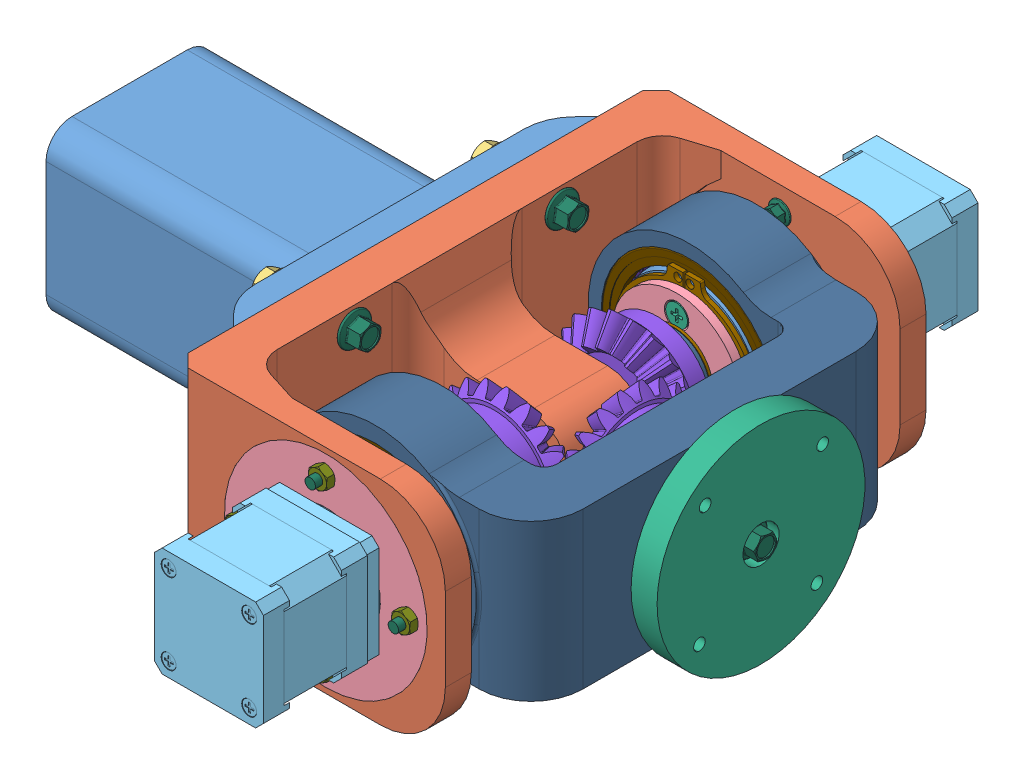
SolidWorks assembly Wrist assembly v2, configuration Default. Lengths in mm.
Overall size (245 113 275).
266 component instances, 29 part files, 123 mates.
Components (placement in the parent):
- Wrist mount-1: Wrist mount [Default] at (124.8037 132.1367 221.4307) x (-1 0 0) z (0 0 -1) size (110 82 140)
- Wrist input frame-2: Wrist input frame [Default] at (124.8037 91.1367 221.4307) x (0 0 -1) z (0 -1 0) size (185 104 82)
- hex flange nut_am-1: hex flange nut_am [M6 hex nut] at (108.8037 165.6367 263.4307) x (0 0 1) z (-1 0 0) size (14.2 14.2 6)
- hex flange nut_am-2: hex flange nut_am [M6 hex nut] at (108.8037 98.6367 263.4307) x (0 0 1) z (-1 0 0) size (14.2 14.2 6)
- Motor sleeve-2: Motor sleeve [Default] at (182.8037 132.1367 313.9307) x (0 0 -1) z (0 -1 0) size (50 78 78)
- 17HS15-1684D-HG10-AR3-1: 17HS15-1684D-HG10-AR3 [Default] at (182.8037 132.1367 123.9307) x (0 -1 0) z (0 0 1) size (42.88 42 103.5)
- 17HS15-1684D-HG10-AR3-2: 17HS15-1684D-HG10-AR3 [Default] at (182.8037 132.1367 318.9307) x (0 -1 0) z (0 0 -1) size (42.88 42 103.5)
- flat head screw_am-7: flat head screw_am [M4 16mm flat head screw] at (165.3037 132.1367 263.9307) x (0 0 1) z (-1 0 0) size (16 8.4 8.4)
- flat head screw_am-8: flat head screw_am [M4 16mm flat head screw] at (182.8037 149.6367 263.9307) x (0 0 1) z (-1 0 0) size (16 8.4 8.4)
- flat head screw_am-9: flat head screw_am [M4 16mm flat head screw] at (200.3037 132.1367 263.9307) x (0 0 1) z (-1 0 0) size (16 8.4 8.4)
- flat head screw_am-11: flat head screw_am [M4 16mm flat head screw] at (182.8037 114.6367 263.9307) x (0 0 1) z (-1 0 0) size (16 8.4 8.4)
- shaft-1: shaft [Default] at (182.8037 132.1367 166.9307) x (0 0 1) z (-0.856245 0.51657 0) size (53 17 17)
- straight miter gear_am-1: straight miter gear_am [A 1C 4MYKW25020] at (182.8037 132.1367 193.8048) x (0 0 1) z (0.856245 -0.51657 0) size (19.66 53.34 53.34)
- shaft-2: shaft [Default] at (182.8037 132.1367 275.9307) x (0 0 -1) z (0.128933 -0.991653 0) size (53 17 17)
- straight miter gear_am-2: straight miter gear_am [A 1C 4MYKW25020] at (182.8037 132.1367 249.0566) x (0 0 -1) z (-0.128933 0.991653 0) size (19.66 53.34 53.34)
- basic external retaining ring_am-1: basic external retaining ring_am [50mm retaining ring] at (182.8037 132.1367 174.1307) x (0.99991 0.013423 0) z (0 0 -1) size (54.93 58.5 1.6)
- basic external retaining ring_am-2: basic external retaining ring_am [50mm retaining ring] at (182.8037 132.1367 267.1307) x (0.99991 0.013423 0) z (0 0 -1) size (54.93 58.5 1.6)
- Wrist output frame-1: Wrist output frame [Default] at (182.8037 132.1367 293.9307) x (0 0 -1) z (0 -1 0) size (151.4 102 78)
- Output shaft-1: Output shaft [Default] at (198.8037 132.1367 221.4307) x (0 -0.779859 0.625955) z (1 0 0) size (18 18 51)
- straight miter gear_am-3: straight miter gear_am [A 1C 4MYKW25020] at (210.4297 132.1367 221.4307) x (-1 0 0) z (0 -0.779859 0.625955) size (19.66 53.34 53.34)
- Motor sleeve-3: Motor sleeve [Default] at (182.8037 132.1367 128.9307) x (0 0 1) z (1 0 0) size (50 78 78)
- hex flange nut_am-5: hex flange nut_am [M6 hex nut] at (108.8037 165.6367 179.4307) x (0 0 1) z (-1 0 0) size (14.2 14.2 6)
- hex flange nut_am-6: hex flange nut_am [M6 hex nut] at (108.8037 98.6367 179.4307) x (0 0 1) z (-1 0 0) size (14.2 14.2 6)
- flat head screw_am-12: flat head screw_am [M4 16mm flat head screw] at (182.8037 149.6367 178.9307) x (0 0 -1) z (1 0 0) size (16 8.4 8.4)
- flat head screw_am-13: flat head screw_am [M4 16mm flat head screw] at (200.3037 132.1367 178.9307) x (0 0 -1) z (1 0 0) size (16 8.4 8.4)
- flat head screw_am-14: flat head screw_am [M4 16mm flat head screw] at (165.3037 132.1367 178.9307) x (0 0 -1) z (1 0 0) size (16 8.4 8.4)
- flat head screw_am-15: flat head screw_am [M4 16mm flat head screw] at (182.8037 114.6367 178.9307) x (0 0 -1) z (1 0 0) size (16 8.4 8.4)
- HK_1412-4: HK_1412 [Default] at (182.8037 132.1367 236.4307) x (0 0 -1) z (0.167203 -0.985923 0) size (12 20 20)
  - HK_1412_3-1: HK_1412_3 [Default] x (1 0 0) z (0 -0.382683 0.92388) size (7.3 2 2)
  - HK_1412_3-2: HK_1412_3 [Default] x (1 0 0) z (0 -0.707107 0.707107) size (7.3 2 2)
  - HK_1412_3-3: HK_1412_3 [Default] x (1 0 0) z (0 -0.92388 0.382683) size (7.3 2 2)
  - HK_1412_3-4: HK_1412_3 [Default] x (1 0 0) z (0 -1 0) size (7.3 2 2)
  - HK_1412_3-5: HK_1412_3 [Default] x (1 0 0) z (0 -0.92388 -0.382683) size (7.3 2 2)
  - HK_1412_3-6: HK_1412_3 [Default] x (1 0 0) z (0 -0.707107 -0.707107) size (7.3 2 2)
  - HK_1412_3-7: HK_1412_3 [Default] x (1 0 0) z (0 -0.382683 -0.92388) size (7.3 2 2)
  - HK_1412_3-8: HK_1412_3 [Default] x (1 0 0) z (0 0 -1) size (7.3 2 2)
  - HK_1412_3-9: HK_1412_3 [Default] x (1 0 0) z (0 0.382683 -0.92388) size (7.3 2 2)
  - HK_1412_3-10: HK_1412_3 [Default] x (1 0 0) z (0 0.707107 -0.707107) size (7.3 2 2)
  - HK_1412_3-11: HK_1412_3 [Default] x (1 0 0) z (0 0.92388 -0.382683) size (7.3 2 2)
  - HK_1412_3-12: HK_1412_3 [Default] x (1 0 0) z (0 1 0) size (7.3 2 2)
  - HK_1412_3-13: HK_1412_3 [Default] x (1 0 0) z (0 0.92388 0.382683) size (7.3 2 2)
  - HK_1412_3-14: HK_1412_3 [Default] x (1 0 0) z (0 0.707107 0.707107) size (7.3 2 2)
  - HK_1412_3-15: HK_1412_3 [Default] x (1 0 0) z (0 0.382683 0.92388) size (7.3 2 2)
  - HK_1412_3-16: HK_1412_3 [Default] at origin size (7.3 2 2)
  - HK_1412_20-1: HK_1412_20 [Default] x (1 0 0) z (0 -0.382683 0.92388) size (7.3 2 2)
  - HK_1412_20-2: HK_1412_20 [Default] x (1 0 0) z (0 -0.707107 0.707107) size (7.3 2 2)
  - HK_1412_20-3: HK_1412_20 [Default] x (1 0 0) z (0 -0.92388 0.382683) size (7.3 2 2)
  - HK_1412_20-4: HK_1412_20 [Default] x (1 0 0) z (0 -1 0) size (7.3 2 2)
  - HK_1412_20-5: HK_1412_20 [Default] x (1 0 0) z (0 -0.92388 -0.382683) size (7.3 2 2)
  - HK_1412_20-6: HK_1412_20 [Default] x (1 0 0) z (0 -0.707107 -0.707107) size (7.3 2 2)
  - HK_1412_20-7: HK_1412_20 [Default] x (1 0 0) z (0 -0.382683 -0.92388) size (7.3 2 2)
  - HK_1412_20-8: HK_1412_20 [Default] x (1 0 0) z (0 0 -1) size (7.3 2 2)
  - HK_1412_20-9: HK_1412_20 [Default] x (1 0 0) z (0 0.382683 -0.92388) size (7.3 2 2)
  - HK_1412_20-10: HK_1412_20 [Default] x (1 0 0) z (0 0.707107 -0.707107) size (7.3 2 2)
  - HK_1412_20-11: HK_1412_20 [Default] x (1 0 0) z (0 0.92388 -0.382683) size (7.3 2 2)
  - HK_1412_20-12: HK_1412_20 [Default] x (1 0 0) z (0 1 0) size (7.3 2 2)
  - HK_1412_20-13: HK_1412_20 [Default] x (1 0 0) z (0 0.92388 0.382683) size (7.3 2 2)
  - HK_1412_20-14: HK_1412_20 [Default] x (1 0 0) z (0 0.707107 0.707107) size (7.3 2 2)
  - HK_1412_20-15: HK_1412_20 [Default] x (1 0 0) z (0 0.382683 0.92388) size (7.3 2 2)
  - HK_1412_20-16: HK_1412_20 [Default] at origin size (7.3 2 2)
  - HK_1412_37-1: HK_1412_37 [Default] at origin size (12 20 20)
- HK_1412-5: HK_1412 [Default] at (182.8037 132.1367 206.4307) x (0 0 1) z (0.606827 -0.794834 0) size (12 20 20)
  - HK_1412_3-1: HK_1412_3 [Default] x (1 0 0) z (0 -0.382683 0.92388) size (7.3 2 2)
  - HK_1412_3-2: HK_1412_3 [Default] x (1 0 0) z (0 -0.707107 0.707107) size (7.3 2 2)
  - HK_1412_3-3: HK_1412_3 [Default] x (1 0 0) z (0 -0.92388 0.382683) size (7.3 2 2)
  - HK_1412_3-4: HK_1412_3 [Default] x (1 0 0) z (0 -1 0) size (7.3 2 2)
  - HK_1412_3-5: HK_1412_3 [Default] x (1 0 0) z (0 -0.92388 -0.382683) size (7.3 2 2)
  - HK_1412_3-6: HK_1412_3 [Default] x (1 0 0) z (0 -0.707107 -0.707107) size (7.3 2 2)
  - HK_1412_3-7: HK_1412_3 [Default] x (1 0 0) z (0 -0.382683 -0.92388) size (7.3 2 2)
  - HK_1412_3-8: HK_1412_3 [Default] x (1 0 0) z (0 0 -1) size (7.3 2 2)
  - HK_1412_3-9: HK_1412_3 [Default] x (1 0 0) z (0 0.382683 -0.92388) size (7.3 2 2)
  - HK_1412_3-10: HK_1412_3 [Default] x (1 0 0) z (0 0.707107 -0.707107) size (7.3 2 2)
  - HK_1412_3-11: HK_1412_3 [Default] x (1 0 0) z (0 0.92388 -0.382683) size (7.3 2 2)
  - HK_1412_3-12: HK_1412_3 [Default] x (1 0 0) z (0 1 0) size (7.3 2 2)
  - HK_1412_3-13: HK_1412_3 [Default] x (1 0 0) z (0 0.92388 0.382683) size (7.3 2 2)
  - HK_1412_3-14: HK_1412_3 [Default] x (1 0 0) z (0 0.707107 0.707107) size (7.3 2 2)
  - HK_1412_3-15: HK_1412_3 [Default] x (1 0 0) z (0 0.382683 0.92388) size (7.3 2 2)
  - HK_1412_3-16: HK_1412_3 [Default] at origin size (7.3 2 2)
  - HK_1412_20-1: HK_1412_20 [Default] x (1 0 0) z (0 -0.382683 0.92388) size (7.3 2 2)
  - HK_1412_20-2: HK_1412_20 [Default] x (1 0 0) z (0 -0.707107 0.707107) size (7.3 2 2)
  - HK_1412_20-3: HK_1412_20 [Default] x (1 0 0) z (0 -0.92388 0.382683) size (7.3 2 2)
  - HK_1412_20-4: HK_1412_20 [Default] x (1 0 0) z (0 -1 0) size (7.3 2 2)
  - HK_1412_20-5: HK_1412_20 [Default] x (1 0 0) z (0 -0.92388 -0.382683) size (7.3 2 2)
  - HK_1412_20-6: HK_1412_20 [Default] x (1 0 0) z (0 -0.707107 -0.707107) size (7.3 2 2)
  - HK_1412_20-7: HK_1412_20 [Default] x (1 0 0) z (0 -0.382683 -0.92388) size (7.3 2 2)
  - HK_1412_20-8: HK_1412_20 [Default] x (1 0 0) z (0 0 -1) size (7.3 2 2)
  - HK_1412_20-9: HK_1412_20 [Default] x (1 0 0) z (0 0.382683 -0.92388) size (7.3 2 2)
  - HK_1412_20-10: HK_1412_20 [Default] x (1 0 0) z (0 0.707107 -0.707107) size (7.3 2 2)
  - HK_1412_20-11: HK_1412_20 [Default] x (1 0 0) z (0 0.92388 -0.382683) size (7.3 2 2)
  - HK_1412_20-12: HK_1412_20 [Default] x (1 0 0) z (0 1 0) size (7.3 2 2)
  - HK_1412_20-13: HK_1412_20 [Default] x (1 0 0) z (0 0.92388 0.382683) size (7.3 2 2)
  - HK_1412_20-14: HK_1412_20 [Default] x (1 0 0) z (0 0.707107 0.707107) size (7.3 2 2)
  - HK_1412_20-15: HK_1412_20 [Default] x (1 0 0) z (0 0.382683 0.92388) size (7.3 2 2)
  - HK_1412_20-16: HK_1412_20 [Default] at origin size (7.3 2 2)
  - HK_1412_37-1: HK_1412_37 [Default] at origin size (12 20 20)
- hex flange machine screw_am-15: hex flange machine screw_am [M4 hex head bolt] at (182.8037 164.1367 143.2307) x (0 0 -1) z (1 0 0) size (20.3 8.5 8.5)
- hex flange machine screw_am-16: hex flange machine screw_am [M4 hex head bolt] at (214.8037 132.1367 143.2307) x (0 0 -1) z (1 0 0) size (20.3 8.5 8.5)
- hex flange machine screw_am-17: hex flange machine screw_am [M4 hex head bolt] at (182.8037 100.1367 143.2307) x (0 0 -1) z (1 0 0) size (20.3 8.5 8.5)
- hex flange machine screw_am-18: hex flange machine screw_am [M4 hex head bolt] at (150.8037 132.1367 143.2307) x (0 0 -1) z (1 0 0) size (20.3 8.5 8.5)
- hex flange machine screw_am-19: hex flange machine screw_am [M4 hex head bolt] at (182.8037 164.1367 299.6307) x (0 0 1) z (-1 0 0) size (20.3 8.5 8.5)
- hex flange machine screw_am-20: hex flange machine screw_am [M4 hex head bolt] at (214.8037 132.1367 299.6307) x (0 0 1) z (-1 0 0) size (20.3 8.5 8.5)
- hex flange machine screw_am-21: hex flange machine screw_am [M4 hex head bolt] at (150.8037 132.1367 299.6307) x (0 0 1) z (-1 0 0) size (20.3 8.5 8.5)
- hex flange machine screw_am-22: hex flange machine screw_am [M4 hex head bolt] at (182.8037 100.1367 299.6307) x (0 0 1) z (-1 0 0) size (20.3 8.5 8.5)
- hex nut style 1_am-2: hex nut style 1_am [M4 hex nut] at (182.8037 164.1367 317.1307) size (7 8.08 3.2)
- hex nut style 1_am-3: hex nut style 1_am [M4 hex nut] at (214.8037 132.1367 317.1307) size (7 8.08 3.2)
- hex nut style 1_am-4: hex nut style 1_am [M4 hex nut] at (150.8037 132.1367 317.1307) size (7 8.08 3.2)
- hex nut style 1_am-5: hex nut style 1_am [M4 hex nut] at (182.8037 100.1367 317.1307) size (7 8.08 3.2)
- hex nut style 1_am-6: hex nut style 1_am [M4 hex nut] at (182.8037 164.1367 125.7307) x (0.923728 0.383049 0) z (0 0 -1) size (7 8.08 3.2)
- hex nut style 1_am-7: hex nut style 1_am [M4 hex nut] at (214.8037 132.1367 125.7307) x (0.923728 0.383049 0) z (0 0 -1) size (7 8.08 3.2)
- hex nut style 1_am-8: hex nut style 1_am [M4 hex nut] at (182.8037 100.1367 125.7307) x (0.923728 0.383049 0) z (0 0 -1) size (7 8.08 3.2)
- hex nut style 1_am-9: hex nut style 1_am [M4 hex nut] at (150.8037 132.1367 125.7307) x (0.923728 0.383049 0) z (0 0 -1) size (7 8.08 3.2)
- NKI_50_25-1: NKI_50_25 [Default] at (182.8037 132.1367 173.9307) x (0 0 -1) z (0.178121 -0.984009 0) size (25 68.42 68)
  - NKI_50_25_37-1: NKI_50_25_37 [Default] x (1 0 0) z (0 -0.189251 0.981929) size (18.8 3.5 3.5)
  - NKI_50_25_37-2: NKI_50_25_37 [Default] x (1 0 0) z (0 -0.371662 0.928368) size (18.8 3.5 3.5)
  - NKI_50_25_37-3: NKI_50_25_37 [Default] x (1 0 0) z (0 -0.540641 0.841254) size (18.8 3.5 3.5)
  - NKI_50_25_37-4: NKI_50_25_37 [Default] x (1 0 0) z (0 -0.690079 0.723734) size (18.8 3.5 3.5)
  - NKI_50_25_37-5: NKI_50_25_37 [Default] x (1 0 0) z (0 -0.814576 0.580057) size (18.8 3.5 3.5)
  - NKI_50_25_37-6: NKI_50_25_37 [Default] x (1 0 0) z (0 -0.909632 0.415415) size (18.8 3.5 3.5)
  - NKI_50_25_37-7: NKI_50_25_37 [Default] x (1 0 0) z (0 -0.971812 0.235759) size (18.8 3.5 3.5)
  - NKI_50_25_37-8: NKI_50_25_37 [Default] x (1 0 0) z (0 -0.998867 0.047582) size (18.8 3.5 3.5)
  - NKI_50_25_37-9: NKI_50_25_37 [Default] x (1 0 0) z (0 -0.989821 -0.142315) size (18.8 3.5 3.5)
  - NKI_50_25_37-10: NKI_50_25_37 [Default] x (1 0 0) z (0 -0.945001 -0.327068) size (18.8 3.5 3.5)
  - NKI_50_25_37-11: NKI_50_25_37 [Default] x (1 0 0) z (0 -0.866025 -0.5) size (18.8 3.5 3.5)
  - NKI_50_25_37-12: NKI_50_25_37 [Default] x (1 0 0) z (0 -0.75575 -0.654861) size (18.8 3.5 3.5)
  - NKI_50_25_37-13: NKI_50_25_37 [Default] x (1 0 0) z (0 -0.618159 -0.786053) size (18.8 3.5 3.5)
  - NKI_50_25_37-14: NKI_50_25_37 [Default] x (1 0 0) z (0 -0.458227 -0.888835) size (18.8 3.5 3.5)
  - NKI_50_25_37-15: NKI_50_25_37 [Default] x (1 0 0) z (0 -0.281733 -0.959493) size (18.8 3.5 3.5)
  - NKI_50_25_37-16: NKI_50_25_37 [Default] x (1 0 0) z (0 -0.095056 -0.995472) size (18.8 3.5 3.5)
  - NKI_50_25_37-17: NKI_50_25_37 [Default] x (1 0 0) z (0 0.095056 -0.995472) size (18.8 3.5 3.5)
  - NKI_50_25_37-18: NKI_50_25_37 [Default] x (1 0 0) z (0 0.281733 -0.959493) size (18.8 3.5 3.5)
  - NKI_50_25_37-19: NKI_50_25_37 [Default] x (1 0 0) z (0 0.458227 -0.888835) size (18.8 3.5 3.5)
  - NKI_50_25_37-20: NKI_50_25_37 [Default] x (1 0 0) z (0 0.618159 -0.786053) size (18.8 3.5 3.5)
  - NKI_50_25_37-21: NKI_50_25_37 [Default] x (1 0 0) z (0 0.75575 -0.654861) size (18.8 3.5 3.5)
  - NKI_50_25_37-22: NKI_50_25_37 [Default] x (1 0 0) z (0 0.866025 -0.5) size (18.8 3.5 3.5)
  - NKI_50_25_37-23: NKI_50_25_37 [Default] x (1 0 0) z (0 0.945001 -0.327068) size (18.8 3.5 3.5)
  - NKI_50_25_37-24: NKI_50_25_37 [Default] x (1 0 0) z (0 0.989821 -0.142315) size (18.8 3.5 3.5)
  - NKI_50_25_37-25: NKI_50_25_37 [Default] x (1 0 0) z (0 0.998867 0.047582) size (18.8 3.5 3.5)
  - NKI_50_25_37-26: NKI_50_25_37 [Default] x (1 0 0) z (0 0.971812 0.235759) size (18.8 3.5 3.5)
  - NKI_50_25_37-27: NKI_50_25_37 [Default] x (1 0 0) z (0 0.909632 0.415415) size (18.8 3.5 3.5)
  - NKI_50_25_37-28: NKI_50_25_37 [Default] x (1 0 0) z (0 0.814576 0.580057) size (18.8 3.5 3.5)
  - NKI_50_25_37-29: NKI_50_25_37 [Default] x (1 0 0) z (0 0.690079 0.723734) size (18.8 3.5 3.5)
  - NKI_50_25_37-30: NKI_50_25_37 [Default] x (1 0 0) z (0 0.540641 0.841254) size (18.8 3.5 3.5)
  - NKI_50_25_37-31: NKI_50_25_37 [Default] x (1 0 0) z (0 0.371662 0.928368) size (18.8 3.5 3.5)
  - NKI_50_25_37-32: NKI_50_25_37 [Default] x (1 0 0) z (0 0.189251 0.981929) size (18.8 3.5 3.5)
  - NKI_50_25_37-33: NKI_50_25_37 [Default] at origin size (18.8 3.5 3.5)
  - NKI_50_25_71-1: NKI_50_25_71 [Default] at origin size (25 68.42 68)
  - NKI_50_25_73-1: NKI_50_25_73 [Default] at origin size (25 55 55)
- NKI_50_25-2: NKI_50_25 [Default] at (182.8037 132.1367 268.9307) x (0 0 1) z (0.40035 -0.916362 0) size (25 68.42 68)
  - NKI_50_25_37-1: NKI_50_25_37 [Default] x (1 0 0) z (0 -0.189251 0.981929) size (18.8 3.5 3.5)
  - NKI_50_25_37-2: NKI_50_25_37 [Default] x (1 0 0) z (0 -0.371662 0.928368) size (18.8 3.5 3.5)
  - NKI_50_25_37-3: NKI_50_25_37 [Default] x (1 0 0) z (0 -0.540641 0.841254) size (18.8 3.5 3.5)
  - NKI_50_25_37-4: NKI_50_25_37 [Default] x (1 0 0) z (0 -0.690079 0.723734) size (18.8 3.5 3.5)
  - NKI_50_25_37-5: NKI_50_25_37 [Default] x (1 0 0) z (0 -0.814576 0.580057) size (18.8 3.5 3.5)
  - NKI_50_25_37-6: NKI_50_25_37 [Default] x (1 0 0) z (0 -0.909632 0.415415) size (18.8 3.5 3.5)
  - NKI_50_25_37-7: NKI_50_25_37 [Default] x (1 0 0) z (0 -0.971812 0.235759) size (18.8 3.5 3.5)
  - NKI_50_25_37-8: NKI_50_25_37 [Default] x (1 0 0) z (0 -0.998867 0.047582) size (18.8 3.5 3.5)
  - NKI_50_25_37-9: NKI_50_25_37 [Default] x (1 0 0) z (0 -0.989821 -0.142315) size (18.8 3.5 3.5)
  - NKI_50_25_37-10: NKI_50_25_37 [Default] x (1 0 0) z (0 -0.945001 -0.327068) size (18.8 3.5 3.5)
  - NKI_50_25_37-11: NKI_50_25_37 [Default] x (1 0 0) z (0 -0.866025 -0.5) size (18.8 3.5 3.5)
  - NKI_50_25_37-12: NKI_50_25_37 [Default] x (1 0 0) z (0 -0.75575 -0.654861) size (18.8 3.5 3.5)
  - NKI_50_25_37-13: NKI_50_25_37 [Default] x (1 0 0) z (0 -0.618159 -0.786053) size (18.8 3.5 3.5)
  - NKI_50_25_37-14: NKI_50_25_37 [Default] x (1 0 0) z (0 -0.458227 -0.888835) size (18.8 3.5 3.5)
  - NKI_50_25_37-15: NKI_50_25_37 [Default] x (1 0 0) z (0 -0.281733 -0.959493) size (18.8 3.5 3.5)
  - NKI_50_25_37-16: NKI_50_25_37 [Default] x (1 0 0) z (0 -0.095056 -0.995472) size (18.8 3.5 3.5)
  - NKI_50_25_37-17: NKI_50_25_37 [Default] x (1 0 0) z (0 0.095056 -0.995472) size (18.8 3.5 3.5)
  - NKI_50_25_37-18: NKI_50_25_37 [Default] x (1 0 0) z (0 0.281733 -0.959493) size (18.8 3.5 3.5)
  - NKI_50_25_37-19: NKI_50_25_37 [Default] x (1 0 0) z (0 0.458227 -0.888835) size (18.8 3.5 3.5)
  - NKI_50_25_37-20: NKI_50_25_37 [Default] x (1 0 0) z (0 0.618159 -0.786053) size (18.8 3.5 3.5)
  - NKI_50_25_37-21: NKI_50_25_37 [Default] x (1 0 0) z (0 0.75575 -0.654861) size (18.8 3.5 3.5)
  - NKI_50_25_37-22: NKI_50_25_37 [Default] x (1 0 0) z (0 0.866025 -0.5) size (18.8 3.5 3.5)
  - NKI_50_25_37-23: NKI_50_25_37 [Default] x (1 0 0) z (0 0.945001 -0.327068) size (18.8 3.5 3.5)
  - NKI_50_25_37-24: NKI_50_25_37 [Default] x (1 0 0) z (0 0.989821 -0.142315) size (18.8 3.5 3.5)
  - NKI_50_25_37-25: NKI_50_25_37 [Default] x (1 0 0) z (0 0.998867 0.047582) size (18.8 3.5 3.5)
  - NKI_50_25_37-26: NKI_50_25_37 [Default] x (1 0 0) z (0 0.971812 0.235759) size (18.8 3.5 3.5)
  - NKI_50_25_37-27: NKI_50_25_37 [Default] x (1 0 0) z (0 0.909632 0.415415) size (18.8 3.5 3.5)
  - NKI_50_25_37-28: NKI_50_25_37 [Default] x (1 0 0) z (0 0.814576 0.580057) size (18.8 3.5 3.5)
  - NKI_50_25_37-29: NKI_50_25_37 [Default] x (1 0 0) z (0 0.690079 0.723734) size (18.8 3.5 3.5)
  - NKI_50_25_37-30: NKI_50_25_37 [Default] x (1 0 0) z (0 0.540641 0.841254) size (18.8 3.5 3.5)
  - NKI_50_25_37-31: NKI_50_25_37 [Default] x (1 0 0) z (0 0.371662 0.928368) size (18.8 3.5 3.5)
  - NKI_50_25_37-32: NKI_50_25_37 [Default] x (1 0 0) z (0 0.189251 0.981929) size (18.8 3.5 3.5)
  - NKI_50_25_37-33: NKI_50_25_37 [Default] at origin size (18.8 3.5 3.5)
  - NKI_50_25_71-1: NKI_50_25_71 [Default] at origin size (25 68.42 68)
  - NKI_50_25_73-1: NKI_50_25_73 [Default] at origin size (25 55 55)
- 7203_BEY-1: 7203_BEY [Default] at (233.8037 132.1367 221.4307) x (-1 0 0) z (0 -0.953266 -0.302132) size (12 40 40)
  - 7203_BEY_3-1: 7203_BEY_3 [Default] x (1 0 0) z (0 -0.587785 0.809017) size (7.14 7.14 7.14)
  - 7203_BEY_3-2: 7203_BEY_3 [Default] x (1 0 0) z (0 -0.951057 0.309017) size (7.14 7.14 7.14)
  - 7203_BEY_3-3: 7203_BEY_3 [Default] x (1 0 0) z (0 -0.951057 -0.309017) size (7.14 7.14 7.14)
  - 7203_BEY_3-4: 7203_BEY_3 [Default] x (1 0 0) z (0 -0.587785 -0.809017) size (7.14 7.14 7.14)
  - 7203_BEY_3-5: 7203_BEY_3 [Default] x (1 0 0) z (0 0 -1) size (7.14 7.14 7.14)
  - 7203_BEY_3-6: 7203_BEY_3 [Default] x (1 0 0) z (0 0.587785 -0.809017) size (7.14 7.14 7.14)
  - 7203_BEY_3-7: 7203_BEY_3 [Default] x (1 0 0) z (0 0.951057 -0.309017) size (7.14 7.14 7.14)
  - 7203_BEY_3-8: 7203_BEY_3 [Default] x (1 0 0) z (0 0.951057 0.309017) size (7.14 7.14 7.14)
  - 7203_BEY_3-9: 7203_BEY_3 [Default] x (1 0 0) z (0 0.587785 0.809017) size (7.14 7.14 7.14)
  - 7203_BEY_3-10: 7203_BEY_3 [Default] at origin size (7.14 7.14 7.14)
  - 7203_BEY_14-1: 7203_BEY_14 [Default] at origin size (12 40 40)
  - 7203_BEY_16-1: 7203_BEY_16 [Default] at origin size (12 26.25 26.25)
- 7203_BEY-2: 7203_BEY [Default] at (233.8037 132.1367 221.4307) x (1 0 0) z (0 0.191508 0.981491) size (12 40 40)
  - 7203_BEY_3-1: 7203_BEY_3 [Default] x (1 0 0) z (0 -0.587785 0.809017) size (7.14 7.14 7.14)
  - 7203_BEY_3-2: 7203_BEY_3 [Default] x (1 0 0) z (0 -0.951057 0.309017) size (7.14 7.14 7.14)
  - 7203_BEY_3-3: 7203_BEY_3 [Default] x (1 0 0) z (0 -0.951057 -0.309017) size (7.14 7.14 7.14)
  - 7203_BEY_3-4: 7203_BEY_3 [Default] x (1 0 0) z (0 -0.587785 -0.809017) size (7.14 7.14 7.14)
  - 7203_BEY_3-5: 7203_BEY_3 [Default] x (1 0 0) z (0 0 -1) size (7.14 7.14 7.14)
  - 7203_BEY_3-6: 7203_BEY_3 [Default] x (1 0 0) z (0 0.587785 -0.809017) size (7.14 7.14 7.14)
  - 7203_BEY_3-7: 7203_BEY_3 [Default] x (1 0 0) z (0 0.951057 -0.309017) size (7.14 7.14 7.14)
  - 7203_BEY_3-8: 7203_BEY_3 [Default] x (1 0 0) z (0 0.951057 0.309017) size (7.14 7.14 7.14)
  - 7203_BEY_3-9: 7203_BEY_3 [Default] x (1 0 0) z (0 0.587785 0.809017) size (7.14 7.14 7.14)
  - 7203_BEY_3-10: 7203_BEY_3 [Default] at origin size (7.14 7.14 7.14)
  - 7203_BEY_14-1: 7203_BEY_14 [Default] at origin size (12 40 40)
  - 7203_BEY_16-1: 7203_BEY_16 [Default] at origin size (12 26.25 26.25)
- 4mm spacer-1: 4mm spacer [Default] at (217.8037 132.1367 221.4307) x (0 -0.351053 0.936356) z (1 0 0) size (20 20 4)
- End effecter mount-1: End effecter mount [Default] at (247.8037 132.1367 221.4307) x (0 -0.740797 -0.671729) z (1 0 0) size (80 80 10)
- hex flange machine screw_am-23: hex flange machine screw_am [M6 25mm hex head bolt] at (259.8037 132.1367 221.4307) x (-1 0 0) z (0 0.362401 -0.932022) size (31.7 12.8 12.8)
- hex flange machine screw_am-24: hex flange machine screw_am [M6 25mm hex head bolt] at (147.5037 165.6367 181.4307) x (-1 0 0) z (0 0.924225 0.381849) size (31.7 12.8 12.8)
- hex flange machine screw_am-25: hex flange machine screw_am [M6 25mm hex head bolt] at (147.5037 165.6367 261.4307) x (-1 0 0) z (0 0.924225 0.381849) size (31.7 12.8 12.8)
- hex flange machine screw_am-26: hex flange machine screw_am [M6 25mm hex head bolt] at (147.5037 98.6367 261.4307) x (-1 0 0) z (0 0.924225 0.381849) size (31.7 12.8 12.8)
- hex flange machine screw_am-27: hex flange machine screw_am [M6 25mm hex head bolt] at (147.5037 98.6367 181.4307) x (-1 0 0) z (0 0.924225 0.381849) size (31.7 12.8 12.8)
- AXK_1528___AS_1528___AS_1528-1: AXK_1528___AS_1528___AS_1528 [Default] at (182.8037 132.1367 180.9307) x (0 0 1) z (-1 0 0) size (4 28 28)
  - AXK_1528___AS_1528___AS_1528_3-1: AXK_1528___AS_1528___AS_1528_3 [Default] x (1 0 0) z (0 -0.309017 0.951057) size (2 5 2)
  - AXK_1528___AS_1528___AS_1528_3-2: AXK_1528___AS_1528___AS_1528_3 [Default] x (1 0 0) z (0 -0.587785 0.809017) size (2 5 2)
  - AXK_1528___AS_1528___AS_1528_3-3: AXK_1528___AS_1528___AS_1528_3 [Default] x (1 0 0) z (0 -0.809017 0.587785) size (2 5 2)
  - AXK_1528___AS_1528___AS_1528_3-4: AXK_1528___AS_1528___AS_1528_3 [Default] x (1 0 0) z (0 -0.951057 0.309017) size (2 5 2)
  - AXK_1528___AS_1528___AS_1528_3-5: AXK_1528___AS_1528___AS_1528_3 [Default] x (1 0 0) z (0 -1 0) size (2 5 2)
  - AXK_1528___AS_1528___AS_1528_3-6: AXK_1528___AS_1528___AS_1528_3 [Default] x (1 0 0) z (0 -0.951057 -0.309017) size (2 5 2)
  - AXK_1528___AS_1528___AS_1528_3-7: AXK_1528___AS_1528___AS_1528_3 [Default] x (1 0 0) z (0 -0.809017 -0.587785) size (2 5 2)
  - AXK_1528___AS_1528___AS_1528_3-8: AXK_1528___AS_1528___AS_1528_3 [Default] x (1 0 0) z (0 -0.587785 -0.809017) size (2 5 2)
  - AXK_1528___AS_1528___AS_1528_3-9: AXK_1528___AS_1528___AS_1528_3 [Default] x (1 0 0) z (0 -0.309017 -0.951057) size (2 5 2)
  - AXK_1528___AS_1528___AS_1528_3-10: AXK_1528___AS_1528___AS_1528_3 [Default] x (1 0 0) z (0 0 -1) size (2 5 2)
  - AXK_1528___AS_1528___AS_1528_3-11: AXK_1528___AS_1528___AS_1528_3 [Default] x (1 0 0) z (0 0.309017 -0.951057) size (2 5 2)
  - AXK_1528___AS_1528___AS_1528_3-12: AXK_1528___AS_1528___AS_1528_3 [Default] x (1 0 0) z (0 0.587785 -0.809017) size (2 5 2)
  - AXK_1528___AS_1528___AS_1528_3-13: AXK_1528___AS_1528___AS_1528_3 [Default] x (1 0 0) z (0 0.809017 -0.587785) size (2 5 2)
  - AXK_1528___AS_1528___AS_1528_3-14: AXK_1528___AS_1528___AS_1528_3 [Default] x (1 0 0) z (0 0.951057 -0.309017) size (2 5 2)
  - AXK_1528___AS_1528___AS_1528_3-15: AXK_1528___AS_1528___AS_1528_3 [Default] x (1 0 0) z (0 1 0) size (2 5 2)
  - AXK_1528___AS_1528___AS_1528_3-16: AXK_1528___AS_1528___AS_1528_3 [Default] x (1 0 0) z (0 0.951057 0.309017) size (2 5 2)
  - AXK_1528___AS_1528___AS_1528_3-17: AXK_1528___AS_1528___AS_1528_3 [Default] x (1 0 0) z (0 0.809017 0.587785) size (2 5 2)
  - AXK_1528___AS_1528___AS_1528_3-18: AXK_1528___AS_1528___AS_1528_3 [Default] x (1 0 0) z (0 0.587785 0.809017) size (2 5 2)
  - AXK_1528___AS_1528___AS_1528_3-19: AXK_1528___AS_1528___AS_1528_3 [Default] x (1 0 0) z (0 0.309017 0.951057) size (2 5 2)
  - AXK_1528___AS_1528___AS_1528_3-20: AXK_1528___AS_1528___AS_1528_3 [Default] at origin size (2 5 2)
  - AXK_1528___AS_1528___AS_1528_24-1: AXK_1528___AS_1528___AS_1528_24 [Default] at origin size (1 28 28)
  - AXK_1528___AS_1528___AS_1528_26-1: AXK_1528___AS_1528___AS_1528_26 [Default] at origin size (1 28 28)
  - AXK_1528___AS_1528___AS_1528_28-1: AXK_1528___AS_1528___AS_1528_28 [Default] at origin size (1.6 28 28)
- 2mm spacer-1: 2mm spacer [Default] at (182.8037 132.1367 184.9307) size (28 28 1.5)
- AXK_1528___AS_1528___AS_1528-2: AXK_1528___AS_1528___AS_1528 [Default] at (182.8037 132.1367 261.9307) x (0 0 1) z (-1 0 0) size (4 28 28)
  - AXK_1528___AS_1528___AS_1528_3-1: AXK_1528___AS_1528___AS_1528_3 [Default] x (1 0 0) z (0 -0.309017 0.951057) size (2 5 2)
  - AXK_1528___AS_1528___AS_1528_3-2: AXK_1528___AS_1528___AS_1528_3 [Default] x (1 0 0) z (0 -0.587785 0.809017) size (2 5 2)
  - AXK_1528___AS_1528___AS_1528_3-3: AXK_1528___AS_1528___AS_1528_3 [Default] x (1 0 0) z (0 -0.809017 0.587785) size (2 5 2)
  - AXK_1528___AS_1528___AS_1528_3-4: AXK_1528___AS_1528___AS_1528_3 [Default] x (1 0 0) z (0 -0.951057 0.309017) size (2 5 2)
  - AXK_1528___AS_1528___AS_1528_3-5: AXK_1528___AS_1528___AS_1528_3 [Default] x (1 0 0) z (0 -1 0) size (2 5 2)
  - AXK_1528___AS_1528___AS_1528_3-6: AXK_1528___AS_1528___AS_1528_3 [Default] x (1 0 0) z (0 -0.951057 -0.309017) size (2 5 2)
  - AXK_1528___AS_1528___AS_1528_3-7: AXK_1528___AS_1528___AS_1528_3 [Default] x (1 0 0) z (0 -0.809017 -0.587785) size (2 5 2)
  - AXK_1528___AS_1528___AS_1528_3-8: AXK_1528___AS_1528___AS_1528_3 [Default] x (1 0 0) z (0 -0.587785 -0.809017) size (2 5 2)
  - AXK_1528___AS_1528___AS_1528_3-9: AXK_1528___AS_1528___AS_1528_3 [Default] x (1 0 0) z (0 -0.309017 -0.951057) size (2 5 2)
  - AXK_1528___AS_1528___AS_1528_3-10: AXK_1528___AS_1528___AS_1528_3 [Default] x (1 0 0) z (0 0 -1) size (2 5 2)
  - AXK_1528___AS_1528___AS_1528_3-11: AXK_1528___AS_1528___AS_1528_3 [Default] x (1 0 0) z (0 0.309017 -0.951057) size (2 5 2)
  - AXK_1528___AS_1528___AS_1528_3-12: AXK_1528___AS_1528___AS_1528_3 [Default] x (1 0 0) z (0 0.587785 -0.809017) size (2 5 2)
  - AXK_1528___AS_1528___AS_1528_3-13: AXK_1528___AS_1528___AS_1528_3 [Default] x (1 0 0) z (0 0.809017 -0.587785) size (2 5 2)
  - AXK_1528___AS_1528___AS_1528_3-14: AXK_1528___AS_1528___AS_1528_3 [Default] x (1 0 0) z (0 0.951057 -0.309017) size (2 5 2)
  - AXK_1528___AS_1528___AS_1528_3-15: AXK_1528___AS_1528___AS_1528_3 [Default] x (1 0 0) z (0 1 0) size (2 5 2)
  - AXK_1528___AS_1528___AS_1528_3-16: AXK_1528___AS_1528___AS_1528_3 [Default] x (1 0 0) z (0 0.951057 0.309017) size (2 5 2)
  - AXK_1528___AS_1528___AS_1528_3-17: AXK_1528___AS_1528___AS_1528_3 [Default] x (1 0 0) z (0 0.809017 0.587785) size (2 5 2)
  - AXK_1528___AS_1528___AS_1528_3-18: AXK_1528___AS_1528___AS_1528_3 [Default] x (1 0 0) z (0 0.587785 0.809017) size (2 5 2)
  - AXK_1528___AS_1528___AS_1528_3-19: AXK_1528___AS_1528___AS_1528_3 [Default] x (1 0 0) z (0 0.309017 0.951057) size (2 5 2)
  - AXK_1528___AS_1528___AS_1528_3-20: AXK_1528___AS_1528___AS_1528_3 [Default] at origin size (2 5 2)
  - AXK_1528___AS_1528___AS_1528_24-1: AXK_1528___AS_1528___AS_1528_24 [Default] at origin size (1 28 28)
  - AXK_1528___AS_1528___AS_1528_26-1: AXK_1528___AS_1528___AS_1528_26 [Default] at origin size (1 28 28)
  - AXK_1528___AS_1528___AS_1528_28-1: AXK_1528___AS_1528___AS_1528_28 [Default] at origin size (1.6 28 28)
- 2mm spacer-2: 2mm spacer [Default] at (182.8037 132.1367 256.4307) x (0.996256 -0.086457 0) z (0 0 1) size (28 28 1.5)
Mates (geometry in assembly coordinates):
- Parallel2: parallel aligned: plane of Wrist mount-1 through (114.8037 173.1367 161.4307) normal (0 1 0)
- Parallel3: parallel anti-aligned: plane of Wrist mount-1 through (124.8037 132.1367 221.4307) normal (1 0 0); plane of Wrist input frame-2 through (124.8037 173.1367 221.4307) normal (-1 0 0)
- Parallel4: parallel aligned: plane of Wrist mount-1 through (114.8037 173.1367 161.4307) normal (0 1 0); plane of Wrist input frame-2 through (124.8037 173.1367 221.4307) normal (0 1 0)
- Coincident2: coincident anti-aligned: plane of Wrist mount-1 through (124.8037 132.1367 221.4307) normal (1 0 0); plane of Wrist input frame-2 through (124.8037 173.1367 221.4307) normal (-1 0 0)
- Coincident71: coincident anti-aligned: plane of Wrist mount-1 through (114.8037 132.1367 221.4307) normal (-1 0 0); plane of hex flange nut_am-1 through (114.8037 171.4102 263.4307) normal (1 0 0)
- Coincident81: coincident anti-aligned: plane of Wrist mount-1 through (114.8037 132.1367 221.4307) normal (-1 0 0); plane of hex flange nut_am-2 through (114.8037 104.4102 263.4307) normal (1 0 0)
- Concentric16: concentric anti-aligned: cylinder of Wrist input frame-2 through (182.8037 132.1367 313.9317) axis (0 0 -1) radius 26; cylinder of Motor sleeve-2 through (182.8037 132.1367 378.0341) axis (0 0 1) radius 25
- Coincident15: coincident anti-aligned: plane of Wrist input frame-2 through (182.8037 132.1367 311.4307) normal (0 0 1); plane of Motor sleeve-2 through (208.8037 132.1367 311.4307) normal (0 0 -1)
- Concentric21: concentric aligned: cylinder of Motor sleeve-2 through (182.8037 132.1367 378.0341) axis (0 0 1) radius 21; cylinder of 17HS15-1684D-HG10-AR3-2 through (182.8037 132.1367 278.9307) axis (0 0 1) radius 21
- Concentric22: concentric aligned: circle of Motor sleeve-2; circle of 17HS15-1684D-HG10-AR3-2
- Coincident22: coincident anti-aligned: plane of Motor sleeve-2 through (203.8037 132.1367 278.9307) normal (0 0 1); plane of 17HS15-1684D-HG10-AR3-2 through (182.8037 132.1367 278.9307) normal (0 0 -1)
- Coincident231: coincident aligned: cone of Motor sleeve-2 through (165.3037 132.1367 263.9307) axis (0 0 1); cone of flat head screw_am-7 through (165.3037 132.1367 264.4307) axis (0 0 1)
- Coincident241: coincident aligned: cone of Motor sleeve-2 through (182.8037 149.6367 263.9307) axis (0 0 1); cone of flat head screw_am-8 through (182.8037 149.6367 264.4307) axis (0 0 1)
- Coincident251: coincident aligned: cone of Motor sleeve-2 through (200.3037 132.1367 263.9307) axis (0 0 1); cone of flat head screw_am-9 through (200.3037 132.1367 264.4307) axis (0 0 1)
- Coincident261: coincident aligned: cone of Motor sleeve-2 through (182.8037 114.6367 263.9307) axis (0 0 1); cone of flat head screw_am-11 through (182.8037 114.6367 264.4307) axis (0 0 1)
- Concentric40: concentric aligned: cylinder of 17HS15-1684D-HG10-AR3-1 through (182.8037 132.1367 171.2307) axis (0 0 -1) radius 4; cylinder of shaft-1 through (182.8037 132.1367 182.9307) axis (0 0 -1) radius 7.5
- Coincident44: coincident anti-aligned: plane of 17HS15-1684D-HG10-AR3-1 through (182.8037 132.1367 187.4307) normal (0 0 1); plane of shaft-1 through (182.8037 132.1367 187.4307) normal (0 0 -1)
- Concentric431: concentric aligned: cylinder of shaft-1 through (182.8037 132.1367 219.9307) axis (0 0 -1) radius 7; cylinder of straight miter gear_am-1 through (182.8037 132.1367 228.8048) axis (0 0 -1) radius 7
- Parallel5: parallel anti-aligned: plane of shaft-1 through (178.6782 128.2022 186.9307) normal (-0.51657 -0.856245 0); plane of straight miter gear_am-1 through (180.1403 122.8822 228.8048) normal (0.51657 0.856245 0)
- Concentric44: concentric aligned: cylinder of 17HS15-1684D-HG10-AR3-2 through (182.8037 132.1367 271.6307) axis (0 0 1) radius 4; cylinder of shaft-2 through (182.8037 132.1367 259.9307) axis (0 0 1) radius 7.5
- Coincident48: coincident anti-aligned: plane of 17HS15-1684D-HG10-AR3-2 through (182.8037 132.1367 255.4307) normal (0 0 -1); plane of shaft-2 through (182.8037 132.1367 255.4307) normal (0 0 1)
- Concentric48: concentric aligned: cylinder of shaft-2 through (182.8037 132.1367 222.9307) axis (0 0 1) radius 7; cylinder of straight miter gear_am-2 through (182.8037 132.1367 214.0566) axis (0 0 1) radius 7
- Parallel6: parallel anti-aligned: plane of shaft-2 through (177.543 129.9401 255.9307) normal (-0.991653 -0.128933 0); plane of straight miter gear_am-2 through (173.259 133.4168 214.0566) normal (0.991653 0.128933 0)
- Parallel7: parallel aligned: plane of Wrist input frame-2 through (124.8037 173.1367 221.4307) normal (0 1 0); plane of basic external retaining ring_am-1 through (182.8037 161.9367 175.7307) normal (0 1 0)
- Concentric531: concentric anti-aligned: cylinder of Motor sleeve-2 through (182.8037 132.1367 378.0341) axis (0 0 1) radius 25; cylinder of basic external retaining ring_am-2 through (182.8037 132.1367 268.7307) axis (0 0 -1) radius 23.6
- Coincident561: coincident anti-aligned: plane of Motor sleeve-2 through (182.8037 132.1367 267.1307) normal (0 0 1); plane of basic external retaining ring_am-2 through (182.8037 132.1367 267.1307) normal (0 0 -1)
- Parallel8: parallel aligned: plane of Wrist input frame-2 through (124.8037 173.1367 221.4307) normal (0 1 0); plane of basic external retaining ring_am-2 through (182.8037 161.9367 268.7307) normal (0 1 0)
- Concentric5371: concentric anti-aligned: cylinder of Output shaft-1 through (221.8037 132.1367 221.4307) axis (-1 0 0) radius 7; cylinder of straight miter gear_am-3 through (175.4296 132.1367 221.4307) axis (1 0 0) radius 7
- Parallel10: parallel anti-aligned: plane of Output shaft-1 through (219.8037 127.5242 218.0804) normal (0 -0.625955 -0.779859); plane of straight miter gear_am-3 through (175.4296 124.3657 215.7429) normal (0 0.625955 0.779859)
- GearMate2: gear = 42 : 42 mm: cylinder of straight miter gear_am-2 through (182.8037 132.1367 256.4307) axis (0 0 -1) radius 21; cylinder of straight miter gear_am-3 through (217.8037 132.1367 221.4307) axis (-1 0 0) radius 21
- Coincident5686: coincident anti-aligned: plane of 17HS15-1684D-HG10-AR3-1 through (182.8037 132.1367 163.9307) normal (0 0 1); plane of Motor sleeve-3 through (182.8037 111.1367 163.9307) normal (0 0 -1)
- Concentric5378: concentric aligned: circle of 17HS15-1684D-HG10-AR3-1; circle of Motor sleeve-3
- Coincident56901: coincident anti-aligned: plane of Wrist mount-1 through (114.8037 132.1367 221.4307) normal (-1 0 0); plane of hex flange nut_am-5 through (114.8037 171.4102 179.4307) normal (1 0 0)
- Coincident56911: coincident anti-aligned: plane of Wrist mount-1 through (114.8037 132.1367 221.4307) normal (-1 0 0); plane of hex flange nut_am-6 through (114.8037 104.4102 179.4307) normal (1 0 0)
- Coincident56921: coincident aligned: cone of Motor sleeve-3 through (182.8037 149.6367 178.9307) axis (0 0 -1); cone of flat head screw_am-12 through (182.8037 149.6367 178.4307) axis (0 0 -1)
- Coincident56931: coincident aligned: cone of Motor sleeve-3 through (200.3037 132.1367 178.9307) axis (0 0 -1); cone of flat head screw_am-13 through (200.3037 132.1367 178.4307) axis (0 0 -1)
- Coincident56941: coincident aligned: cone of Motor sleeve-3 through (165.3037 132.1367 178.9307) axis (0 0 -1); cone of flat head screw_am-14 through (165.3037 132.1367 178.4307) axis (0 0 -1)
- Coincident56951: coincident aligned: cone of Motor sleeve-3 through (182.8037 114.6367 178.9307) axis (0 0 -1); cone of flat head screw_am-15 through (182.8037 114.6367 178.4307) axis (0 0 -1)
- Concentric53836: concentric anti-aligned: cylinder of shaft-2 through (182.8037 132.1367 222.9307) axis (0 0 1) radius 7; circle of HK_1412-4/HK_1412_37-1
- Coincident56952: coincident anti-aligned: circle of Wrist input frame-2; plane of HK_1412-4/HK_1412_37-1 through (190.1982 133.3907 224.4307) normal (0 0 -1)
- Concentric53837: concentric anti-aligned: cylinder of shaft-1 through (182.8037 132.1367 219.9307) axis (0 0 -1) radius 7; cylinder of HK_1412-5/HK_1412_37-1 through (182.8037 132.1367 256.4307) axis (0 0 1) radius 10
- Coincident56955: coincident aligned: circle of Wrist input frame-2; plane of HK_1412-5/HK_1412_37-1 through (176.8425 127.5855 218.4307) normal (0 0 1)
- Concentric53841: concentric anti-aligned: cylinder of Wrist input frame-2 through (182.8037 132.1367 128.9297) axis (0 0 1) radius 26; cylinder of Motor sleeve-3 through (182.8037 132.1367 64.8273) axis (0 0 -1) radius 25
- Coincident56956: coincident anti-aligned: plane of Wrist input frame-2 through (182.8037 132.1367 131.4307) normal (0 0 -1); plane of Motor sleeve-3 through (182.8037 106.1367 131.4307) normal (0 0 1)
- Concentric53843: concentric aligned: cylinder of Wrist input frame-2 through (182.8037 164.1367 311.4307) axis (0 0 1) radius 2.25; cylinder of Motor sleeve-2 through (182.8037 164.1367 313.9307) axis (0 0 1) radius 2.25
- Concentric53844: concentric aligned: cylinder of Wrist input frame-2 through (182.8037 164.1367 131.4307) axis (0 0 -1) radius 2.25; cylinder of Motor sleeve-3 through (182.8037 164.1367 128.9307) axis (0 0 -1) radius 2.25
- Concentric538451: concentric anti-aligned: cylinder of Wrist input frame-2 through (182.8037 164.1367 131.4307) axis (0 0 -1) radius 2.25; cylinder of hex flange machine screw_am-15 through (182.8037 164.1367 168.6307) axis (0 0 1) radius 2
- Coincident569571: coincident anti-aligned: plane of Wrist input frame-2 through (228.8037 173.1367 138.9307) normal (0 0 1); plane of hex flange machine screw_am-15 through (182.8037 166.1367 138.9307) normal (0 0 -1)
- Concentric538461: concentric anti-aligned: cylinder of Wrist input frame-2 through (214.8037 132.1367 131.4307) axis (0 0 -1) radius 2.25; cylinder of hex flange machine screw_am-16 through (214.8037 132.1367 168.6307) axis (0 0 1) radius 2
- Coincident569581: coincident anti-aligned: plane of Wrist input frame-2 through (228.8037 173.1367 138.9307) normal (0 0 1); plane of hex flange machine screw_am-16 through (214.8037 134.1367 138.9307) normal (0 0 -1)
- Concentric538471: concentric anti-aligned: cylinder of Wrist input frame-2 through (182.8037 100.1367 131.4307) axis (0 0 -1) radius 2.25; cylinder of hex flange machine screw_am-17 through (182.8037 100.1367 168.6307) axis (0 0 1) radius 2
- Coincident569591: coincident anti-aligned: plane of Wrist input frame-2 through (228.8037 173.1367 138.9307) normal (0 0 1); plane of hex flange machine screw_am-17 through (182.8037 102.1367 138.9307) normal (0 0 -1)
- Concentric538481: concentric anti-aligned: cylinder of Wrist input frame-2 through (150.8037 132.1367 131.4307) axis (0 0 -1) radius 2.25; cylinder of hex flange machine screw_am-18 through (150.8037 132.1367 168.6307) axis (0 0 1) radius 2
- Coincident569601: coincident anti-aligned: plane of Wrist input frame-2 through (228.8037 173.1367 138.9307) normal (0 0 1); plane of hex flange machine screw_am-18 through (150.8037 134.1367 138.9307) normal (0 0 -1)
- Concentric538491: concentric anti-aligned: cylinder of Wrist input frame-2 through (182.8037 164.1367 311.4307) axis (0 0 1) radius 2.25; cylinder of hex flange machine screw_am-19 through (182.8037 164.1367 274.2307) axis (0 0 -1) radius 2
- Coincident569611: coincident anti-aligned: plane of Wrist input frame-2 through (228.8037 173.1367 303.9307) normal (0 0 -1); plane of hex flange machine screw_am-19 through (182.8037 166.1367 303.9307) normal (0 0 1)
- Concentric538501: concentric anti-aligned: cylinder of Wrist input frame-2 through (214.8037 132.1367 311.4307) axis (0 0 1) radius 2.25; cylinder of hex flange machine screw_am-20 through (214.8037 132.1367 274.2307) axis (0 0 -1) radius 2
- Coincident569621: coincident anti-aligned: plane of Wrist input frame-2 through (228.8037 173.1367 303.9307) normal (0 0 -1); plane of hex flange machine screw_am-20 through (214.8037 134.1367 303.9307) normal (0 0 1)
- Concentric538511: concentric anti-aligned: cylinder of Wrist input frame-2 through (150.8037 132.1367 311.4307) axis (0 0 1) radius 2.25; cylinder of hex flange machine screw_am-21 through (150.8037 132.1367 274.2307) axis (0 0 -1) radius 2
- Coincident569631: coincident anti-aligned: plane of Wrist input frame-2 through (228.8037 173.1367 303.9307) normal (0 0 -1); plane of hex flange machine screw_am-21 through (150.8037 134.1367 303.9307) normal (0 0 1)
- Concentric538521: concentric anti-aligned: cylinder of Wrist input frame-2 through (182.8037 100.1367 311.4307) axis (0 0 1) radius 2.25; cylinder of hex flange machine screw_am-22 through (182.8037 100.1367 274.2307) axis (0 0 -1) radius 2
- Coincident569641: coincident anti-aligned: plane of Wrist input frame-2 through (228.8037 173.1367 303.9307) normal (0 0 -1); plane of hex flange machine screw_am-22 through (182.8037 102.1367 303.9307) normal (0 0 1)
- Concentric538541: concentric aligned: cylinder of Motor sleeve-2 through (182.8037 164.1367 313.9307) axis (0 0 1) radius 2.25; cylinder of hex nut style 1_am-2 through (182.8037 164.1367 292.0932) axis (0 0 1) radius 2
- Coincident569661: coincident anti-aligned: plane of Motor sleeve-2 through (221.8037 132.1367 313.9307) normal (0 0 1); plane of hex nut style 1_am-2 through (182.8037 168.1782 313.9307) normal (0 0 -1)
- Concentric538551: concentric aligned: cylinder of Motor sleeve-2 through (214.8037 132.1367 313.9307) axis (0 0 1) radius 2.25; cylinder of hex nut style 1_am-3 through (214.8037 132.1367 292.0932) axis (0 0 1) radius 2
- Coincident569671: coincident anti-aligned: plane of Motor sleeve-2 through (221.8037 132.1367 313.9307) normal (0 0 1); plane of hex nut style 1_am-3 through (214.8037 136.1782 313.9307) normal (0 0 -1)
- Concentric538561: concentric aligned: cylinder of Motor sleeve-2 through (150.8037 132.1367 313.9307) axis (0 0 1) radius 2.25; cylinder of hex nut style 1_am-4 through (150.8037 132.1367 292.0932) axis (0 0 1) radius 2
- Coincident569681: coincident anti-aligned: plane of Motor sleeve-2 through (221.8037 132.1367 313.9307) normal (0 0 1); plane of hex nut style 1_am-4 through (150.8037 136.1782 313.9307) normal (0 0 -1)
- Concentric538571: concentric aligned: cylinder of Motor sleeve-2 through (182.8037 100.1367 313.9307) axis (0 0 1) radius 2.25; cylinder of hex nut style 1_am-5 through (182.8037 100.1367 292.0932) axis (0 0 1) radius 2
- Coincident569691: coincident anti-aligned: plane of Motor sleeve-2 through (221.8037 132.1367 313.9307) normal (0 0 1); plane of hex nut style 1_am-5 through (182.8037 104.1782 313.9307) normal (0 0 -1)
- Concentric538581: concentric anti-aligned: cylinder of hex flange machine screw_am-15 through (182.8037 164.1367 168.6307) axis (0 0 1) radius 2; cylinder of hex nut style 1_am-6 through (182.8037 164.1367 150.7682) axis (0 0 -1) radius 2
- Coincident569701: coincident anti-aligned: plane of Motor sleeve-3 through (182.8037 93.1367 128.9307) normal (0 0 -1); plane of hex nut style 1_am-6 through (184.3518 160.4035 128.9307) normal (0 0 1)
- Concentric538591: concentric anti-aligned: cylinder of hex flange machine screw_am-16 through (214.8037 132.1367 168.6307) axis (0 0 1) radius 2; cylinder of hex nut style 1_am-7 through (214.8037 132.1367 150.7682) axis (0 0 -1) radius 2
- Coincident569711: coincident anti-aligned: plane of Motor sleeve-3 through (182.8037 93.1367 128.9307) normal (0 0 -1); plane of hex nut style 1_am-7 through (216.3518 128.4035 128.9307) normal (0 0 1)
- Concentric538601: concentric anti-aligned: cylinder of hex flange machine screw_am-17 through (182.8037 100.1367 168.6307) axis (0 0 1) radius 2; cylinder of hex nut style 1_am-8 through (182.8037 100.1367 150.7682) axis (0 0 -1) radius 2
- Coincident569721: coincident anti-aligned: plane of Motor sleeve-3 through (182.8037 93.1367 128.9307) normal (0 0 -1); plane of hex nut style 1_am-8 through (184.3518 96.4035 128.9307) normal (0 0 1)
- Concentric538611: concentric anti-aligned: cylinder of hex flange machine screw_am-18 through (150.8037 132.1367 168.6307) axis (0 0 1) radius 2; cylinder of hex nut style 1_am-9 through (150.8037 132.1367 150.7682) axis (0 0 -1) radius 2
- Coincident569731: coincident anti-aligned: plane of Motor sleeve-3 through (182.8037 93.1367 128.9307) normal (0 0 -1); plane of hex nut style 1_am-9 through (152.3518 128.4035 128.9307) normal (0 0 1)
- Concentric53863: concentric anti-aligned: circle of basic external retaining ring_am-1; circle of Motor sleeve-3
- Coincident5697352: coincident: point of Wrist input frame-2; moEndPointRef_w of Wrist output frame-1
- Coincident5697355: coincident aligned: plane of basic external retaining ring_am-1 through (182.8037 132.1367 175.7307) normal (0 0 1); circle of Motor sleeve-3
- Concentric5386153: concentric aligned: cylinder of Motor sleeve-2 through (182.8037 132.1367 378.0341) axis (0 0 1) radius 25; cylinder of Wrist output frame-1 through (182.8037 132.1367 268.9307) axis (0 0 1) radius 39
- GearMate3: gear = 42 : 42 mm: cylinder of straight miter gear_am-1 through (182.8037 132.1367 186.4307) axis (0 0 1) radius 21; cylinder of straight miter gear_am-3 through (217.8037 132.1367 221.4307) axis (-1 0 0) radius 21
- Concentric5386154: concentric aligned: cylinder of Motor sleeve-3 through (182.8037 132.1367 64.8273) axis (0 0 -1) radius 25; cylinder of NKI_50_25-1/NKI_50_25_73-1 through (182.8037 132.1367 148.9307) axis (0 0 -1) radius 25
- Concentric5386155: concentric aligned: cylinder of Motor sleeve-2 through (182.8037 132.1367 378.0341) axis (0 0 1) radius 26; cylinder of NKI_50_25-2/NKI_50_25_73-1 through (182.8037 132.1367 293.9307) axis (0 0 1) radius 25
- Distance5: distance = 0 mm anti-aligned: plane of Wrist output frame-1 through (182.8037 132.1367 148.9307) normal (0 0 1); plane of NKI_50_25-1/NKI_50_25_71-1 through (213.308 137.6585 148.9307) normal (0 0 -1)
- Coincident5697356: coincident anti-aligned: plane of Motor sleeve-2 through (207.8037 132.1367 293.9307) normal (0 0 -1); plane of NKI_50_25-2/NKI_50_25_71-1 through (154.3965 119.7259 293.9307) normal (0 0 1)
- Distance7: distance = 19 mm anti-aligned: plane of straight miter gear_am-3 through (217.8037 132.1367 221.4307) normal (1 0 0); plane of Output shaft-1 through (198.8037 132.1367 221.4307) normal (-1 0 0)
- Distance9: distance = 4 mm anti-aligned: plane of straight miter gear_am-3 through (217.8037 132.1367 221.4307) normal (1 0 0); plane of Wrist output frame-1 through (221.8037 132.1367 293.9307) normal (-1 0 0)
- Concentric5386157: concentric aligned: circle of Wrist mount-1; circle of Wrist input frame-2
- Parallel11: parallel aligned: plane of Wrist mount-1 through (114.8037 173.1367 161.4307) normal (0 1 0); plane of Wrist input frame-2 through (124.8037 173.1367 221.4307) normal (0 1 0)
- Concentric5386159: concentric aligned: cylinder of Wrist output frame-1 through (241.8047 132.1367 221.4307) axis (-1 0 0) radius 20; cylinder of Output shaft-1 through (249.8037 132.1367 221.4307) axis (-1 0 0) radius 8.5
- Concentric5386160: concentric aligned: cylinder of Output shaft-1 through (249.8037 132.1367 221.4307) axis (-1 0 0) radius 8.5; cylinder of 7203_BEY-1/7203_BEY_16-1 through (221.8037 132.1367 221.4307) axis (-1 0 0) radius 8.5
- Distance11: distance = 0 mm aligned: plane of 7203_BEY-1/7203_BEY_16-1 through (221.8037 134.8861 212.756) normal (-1 0 0); plane of Wrist output frame-1 through (221.8037 132.1367 293.9307) normal (-1 0 0)
- Concentric5386161: concentric anti-aligned: cylinder of Output shaft-1 through (249.8037 132.1367 221.4307) axis (-1 0 0) radius 8.5; cylinder of 7203_BEY-2/7203_BEY_16-1 through (245.8037 132.1367 221.4307) axis (1 0 0) radius 8.5
- Coincident5697357: coincident anti-aligned: plane of 7203_BEY-1/7203_BEY_14-1 through (233.8037 137.9981 202.9373) normal (1 0 0); plane of 7203_BEY-2/7203_BEY_14-1 through (233.8037 151.1777 217.7154) normal (-1 0 0)
- Distance12: distance = 0 mm anti-aligned: plane of 4mm spacer-1 through (221.8037 132.1367 221.4307) normal (1 0 0); plane of 7203_BEY-1/7203_BEY_16-1 through (221.8037 134.8861 212.756) normal (-1 0 0)
- Concentric5386162: concentric aligned: cylinder of Output shaft-1 through (221.8037 132.1367 221.4307) axis (-1 0 0) radius 7; cylinder of 4mm spacer-1 through (221.8037 132.1367 221.4307) axis (-1 0 0) radius 7
- Concentric5386163: concentric aligned: cylinder of Output shaft-1 through (249.8037 132.1367 221.4307) axis (1 0 0) radius 2.5; cylinder of End effecter mount-1 through (257.8037 132.1367 221.4307) axis (1 0 0) radius 6.975
- Coincident5697359: coincident anti-aligned: plane of Output shaft-1 through (249.8037 132.1367 221.4307) normal (1 0 0); plane of End effecter mount-1 through (249.8037 132.1367 221.4307) normal (-1 0 0)
- Concentric53861641: concentric aligned: cylinder of End effecter mount-1 through (257.8037 132.1367 221.4307) axis (1 0 0) radius 3.3; cylinder of hex flange machine screw_am-23 through (285.2037 132.1367 221.4307) axis (1 0 0) radius 3
- Coincident56973601: coincident anti-aligned: plane of End effecter mount-1 through (253.1037 129.6921 219.214) normal (1 0 0); plane of hex flange machine screw_am-23 through (253.1037 134.9328 222.5179) normal (-1 0 0)
- Concentric538616451: concentric anti-aligned: cylinder of Wrist input frame-2 through (124.8037 165.6367 181.4307) axis (-1 0 0) radius 3.3; cylinder of M6 25mm hex head bolt-2 through (172.9037 165.6367 181.4307) axis (1 0 0) radius 3
- Coincident569736051: coincident anti-aligned: plane of Wrist input frame-2 through (140.8037 259.3414 152.2439) normal (1 0 0); plane of M6 25mm hex head bolt-2 through (140.8037 164.4912 184.2034) normal (-1 0 0)
- Concentric538616461: concentric anti-aligned: cylinder of Wrist input frame-2 through (124.8037 165.6367 261.4307) axis (-1 0 0) radius 3.3; cylinder of M6 25mm hex head bolt-3 through (172.9037 165.6367 261.4307) axis (1 0 0) radius 3
- Coincident569736061: coincident anti-aligned: plane of Wrist input frame-2 through (140.8037 259.3414 290.6175) normal (1 0 0); plane of M6 25mm hex head bolt-3 through (140.8037 164.4912 264.2034) normal (-1 0 0)
- Concentric538616471: concentric anti-aligned: cylinder of Wrist input frame-2 through (124.8037 98.6367 261.4307) axis (-1 0 0) radius 3.3; cylinder of M6 25mm hex head bolt-4 through (172.9037 98.6367 261.4307) axis (1 0 0) radius 3
- Coincident569736071: coincident anti-aligned: plane of Wrist input frame-2 through (140.8037 259.3414 290.6175) normal (1 0 0); plane of M6 25mm hex head bolt-4 through (140.8037 97.4912 264.2034) normal (-1 0 0)
- Concentric538616481: concentric anti-aligned: cylinder of Wrist input frame-2 through (124.8037 98.6367 181.4307) axis (-1 0 0) radius 3.3; cylinder of M6 25mm hex head bolt-5 through (172.9037 98.6367 181.4307) axis (1 0 0) radius 3
- Coincident569736081: coincident anti-aligned: plane of Wrist input frame-2 through (140.8037 259.3414 152.2439) normal (1 0 0); plane of M6 25mm hex head bolt-5 through (140.8037 97.4912 184.2034) normal (-1 0 0)
- Parallel12: parallel anti-aligned: plane of straight miter gear_am-3 through (175.4296 124.3657 215.7429) normal (0 0.625955 0.779859); plane of hex flange machine screw_am-23 through (253.1037 127.8319 219.7568) normal (0 -0.625955 -0.779859)
- Lock1: lock: unknown of End effecter mount-1; unknown of hex flange machine screw_am-23
- Concentric538616482: concentric aligned: cylinder of shaft-1 through (182.8037 132.1367 182.9307) axis (0 0 -1) radius 7.5; cylinder of Motor sleeve-3 through (182.8037 132.1367 64.8273) axis (0 0 -1) radius 8.5
- Concentric538616483: concentric anti-aligned: cylinder of shaft-1 through (182.8037 132.1367 182.9307) axis (0 0 -1) radius 7.5; circle of AXK_1528___AS_1528___AS_1528-1/AXK_1528___AS_1528___AS_1528_24-1
- Coincident569736082: coincident aligned: circle of shaft-1; plane of AXK_1528___AS_1528___AS_1528-1/AXK_1528___AS_1528___AS_1528_24-1 through (182.8037 139.6367 182.9307) normal (0 0 1)
- Concentric538616484: concentric aligned: cylinder of shaft-1 through (182.8037 132.1367 219.9307) axis (0 0 -1) radius 7; cylinder of 2mm spacer-1 through (182.8037 132.1367 186.4307) axis (0 0 -1) radius 7
- Coincident569736083: coincident anti-aligned: plane of shaft-1 through (182.8037 132.1367 184.9307) normal (0 0 1); plane of 2mm spacer-1 through (182.8037 132.1367 184.9307) normal (0 0 -1)
- Coincident569736084: coincident anti-aligned: plane of straight miter gear_am-1 through (182.8037 132.1367 186.4307) normal (0 0 -1); plane of 2mm spacer-1 through (182.8037 132.1367 186.4307) normal (0 0 1)
- Concentric538616485: concentric anti-aligned: cylinder of shaft-2 through (182.8037 132.1367 259.9307) axis (0 0 1) radius 7.5; cylinder of AXK_1528___AS_1528___AS_1528-2/AXK_1528___AS_1528___AS_1528_28-1 through (182.8037 132.1367 262.7307) axis (0 0 -1) radius 7.5
- Coincident569736085: coincident aligned: circle of shaft-2; plane of AXK_1528___AS_1528___AS_1528-2/AXK_1528___AS_1528___AS_1528_26-1 through (182.8037 146.1367 259.9307) normal (0 0 -1)
- Concentric538616486: concentric aligned: cylinder of shaft-2 through (182.8037 132.1367 257.9307) axis (0 0 1) radius 8.5; circle of 2mm spacer-2
- Coincident569736086: coincident anti-aligned: plane of shaft-2 through (182.8037 132.1367 257.9307) normal (0 0 -1); plane of 2mm spacer-2 through (182.8037 132.1367 257.9307) normal (0 0 1)
- Coincident569736087: coincident anti-aligned: plane of straight miter gear_am-2 through (182.8037 132.1367 256.4307) normal (0 0 1); plane of 2mm spacer-2 through (182.8037 132.1367 256.4307) normal (0 0 -1)
